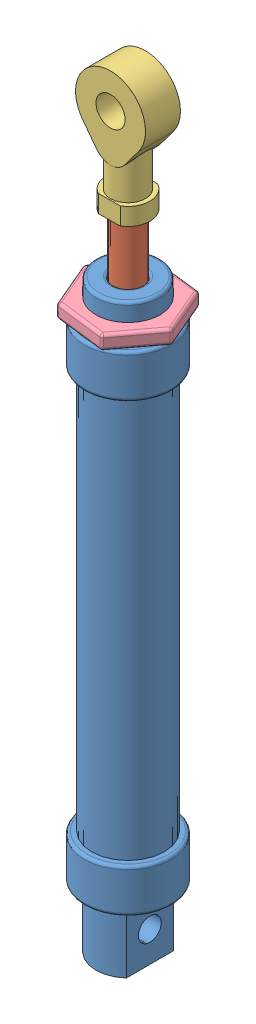
SolidWorks assembly pneu20x100, configuration Default. Lengths in mm.
Overall size (38.08 265 34.43).
4 component instances, 4 part files, 5 mates.
Components (placement in the parent):
- cylinder-1: cylinder [Default] at (86.9073 20.3579 160.9482) size (30 201 30)
- rod20x100-1: rod20x100 [Default] at (86.9073 65.3528 160.9482) x (-0.999356 0 0.035877) z (-0.035877 0 -0.999356) size (10 150 10)
- eye-1: eye [Default] at (86.9073 206.3579 160.9482) x (-1 0 0) z (0 0 -1) size (24 44 13.04)
- nut-1: nut [Default] at (86.9073 175.294 160.9482) x (0.991847 0 0.127432) z (-0.127432 0 0.991847) size (34.5 5 30.28)
Mates (geometry in assembly coordinates):
- Concentric1: concentric anti-aligned: cylinder of cylinder-1 through (86.9073 166.3579 160.9482) axis (0 1 0) radius 5; cylinder of rod20x100-1 through (86.9073 222.7405 160.9482) axis (0 -1 0) radius 5
- Lock1: lock: unknown of rod20x100-1; unknown of eye-1
- Lock2: lock: unknown of cylinder-1; unknown of nut-1
- Perpendicular1: perpendicular: plane of cylinder-1 through (94.4073 6.3579 160.9482) normal (1 0 0); plane of eye-1 through (86.9073 235.7455 166.9482) normal (0 0 1)
- Distance1: distance = 20 mm anti-aligned: plane of eye-1 through (86.9073 206.3579 160.9482) normal (0 -1 0); plane of cylinder-1 through (86.9073 186.3579 160.9482) normal (0 1 0)
